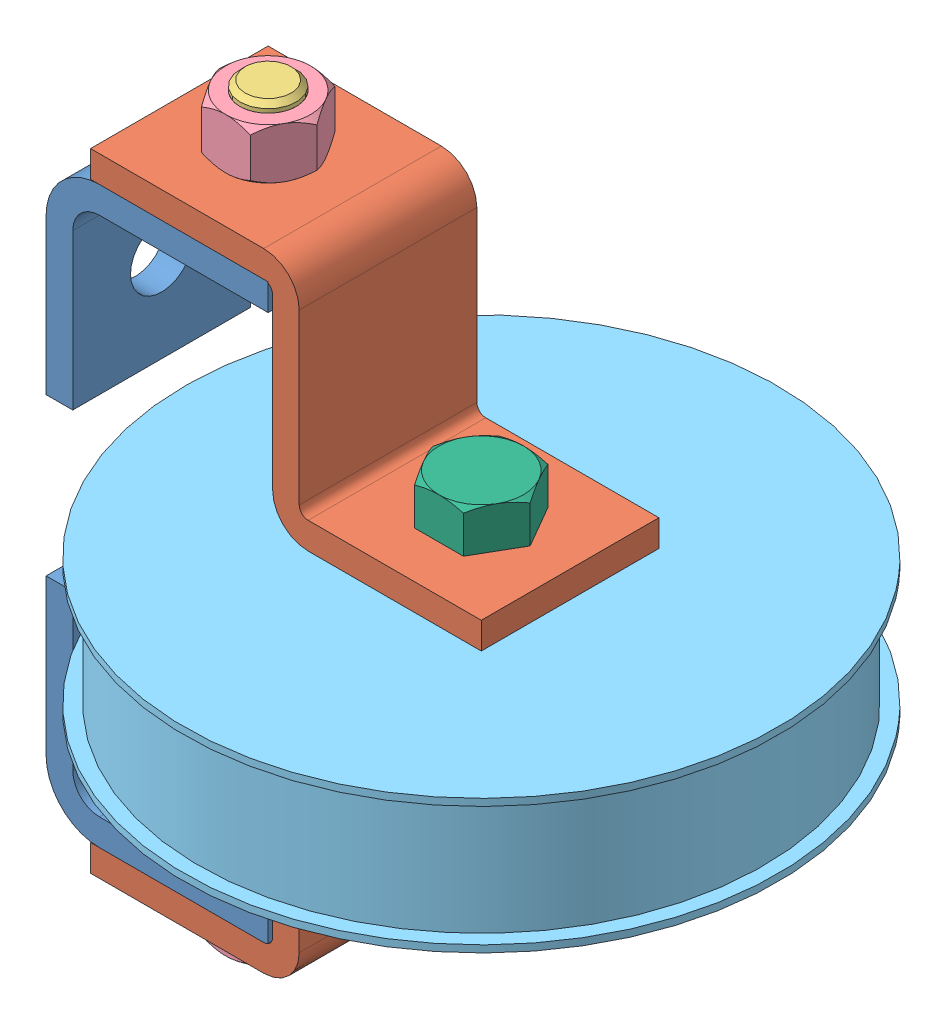
SolidWorks assembly Large Pulley Mount, configuration Default. Lengths in mm.
Overall size (187.97 168.14 187.97).
11 component instances, 5 part files, 17 mates.
Components (placement in the parent):
- P1026 - Unistrut 2-Hole 90 deg Fitting-1: P1026 - Unistrut 2-Hole 90 deg Fitting [Default] at (18.6827 -44.2712 5.2371) size (50 47 40)
- P1347 - Unistrut 2-Hole Z Fitting-1: P1347 - Unistrut 2-Hole Z Fitting [Default] at (28.6827 8.7288 -34.7629) x (1 0 0) z (0 0 -1) size (88 54 40)
- hex bolt_ai-3: hex bolt_ai [HBOLT 0.5000-13x1x1-N] at (48.6827 -12.5168 -14.7629) x (0 1 0) z (0 0 1) size (34.65 22 19.05)
- hex nut_ai-2: hex nut_ai [HNUT 0.5000-20-D-N] at (48.6827 20.108 -14.7629) x (0.866025 0 -0.5) z (0 1 0) size (19.05 22 11.38)
- Wide Pulley-2: Wide Pulley [5"x0.5"] at (96.6827 -61.9399 -14.7629) x (0.762017 0 -0.647557) z (0 -1 0) size (133.35 133.35 30.16)
- hex bolt_ai-2: hex bolt_ai [HBOLT 0.5000-20x3x3-N] at (96.6827 -30.0256 -14.7629) x (0 -1 0) z (0 0 1) size (85.45 22 19.05)
- P1026 - Unistrut 2-Hole 90 deg Fitting-2: P1026 - Unistrut 2-Hole 90 deg Fitting [Default] at (18.6827 -79.6087 -34.7629) x (1 0 0) z (0 0 -1) size (50 47 40)
- P1347 - Unistrut 2-Hole Z Fitting-2: P1347 - Unistrut 2-Hole Z Fitting [Default] at (28.6827 -132.6087 5.2371) size (88 54 40)
- hex bolt_ai-4: hex bolt_ai [HBOLT 0.5000-13x1x1-N] at (48.6827 -111.3631 -14.7629) x (0 -1 0) z (0 0 -1) size (34.65 22 19.05)
- hex nut_ai-3: hex nut_ai [HNUT 0.5000-20-D-N] at (48.6827 -132.6087 -14.7629) x (0.866025 0 -0.5) z (0 1 0) size (19.05 22 11.38)
- hex nut_ai-4: hex nut_ai [HNUT 0.5000-20-D-N] at (96.6827 -95.9879 -14.7629) x (0.866025 0 0.5) z (0 -1 0) size (19.05 22 11.38)
Mates (geometry in assembly coordinates):
- Concentric11: concentric aligned: cylinder of P1026 - Unistrut 2-Hole 90 deg Fitting-1 through (48.6827 -3.2712 -14.7629) axis (0 -1 0) radius 7; cylinder of hex bolt_ai-3 through (48.6827 -12.5168 -14.7629) axis (0 -1 0) radius 6.35
- Coincident21: coincident anti-aligned: plane of P1026 - Unistrut 2-Hole 90 deg Fitting-1 through (24.6827 -3.2712 5.2371) normal (0 -1 0); plane of hex bolt_ai-3 through (37.6841 -3.2712 -14.7629) normal (0 1 0)
- Concentric2: concentric anti-aligned: cylinder of P1347 - Unistrut 2-Hole Z Fitting-1 through (48.6827 8.7288 -14.7629) axis (0 1 0) radius 7; cylinder of hex bolt_ai-3 through (48.6827 -12.5168 -14.7629) axis (0 -1 0) radius 6.35
- Coincident5: coincident anti-aligned: plane of P1026 - Unistrut 2-Hole 90 deg Fitting-1 through (68.6827 2.7288 -34.7629) normal (0 1 0); plane of P1347 - Unistrut 2-Hole Z Fitting-1 through (28.6827 2.7288 5.2371) normal (0 -1 0)
- Parallel2: parallel aligned: plane of P1026 - Unistrut 2-Hole 90 deg Fitting-1 through (18.6827 2.7288 -34.7629) normal (-1 0 0); plane of P1347 - Unistrut 2-Hole Z Fitting-1 through (28.6827 8.7288 -34.7629) normal (-1 0 0)
- Concentric41: concentric anti-aligned: cylinder of hex bolt_ai-3 through (48.6827 -12.5168 -14.7629) axis (0 -1 0) radius 6.35; cylinder of hex nut_ai-2 through (48.6827 -4.9295 -14.7629) axis (0 1 0) radius 6.35
- Coincident81: coincident anti-aligned: plane of P1347 - Unistrut 2-Hole Z Fitting-1 through (116.6827 8.7288 -34.7629) normal (0 1 0); plane of hex nut_ai-2 through (43.1834 8.7288 -24.2879) normal (0 -1 0)
- Parallel3: parallel aligned: plane of hex bolt_ai-3 through (43.1834 -3.2712 -24.2879) normal (0 0 -1); plane of hex nut_ai-2 through (54.1819 8.7288 -24.2879) normal (0 0 -1)
- Parallel4: parallel aligned: plane of P1026 - Unistrut 2-Hole 90 deg Fitting-1 through (18.6827 -44.2712 -34.7629) normal (0 0 -1); plane of hex bolt_ai-3 through (43.1834 -3.2712 -24.2879) normal (0 0 -1)
- Concentric51: concentric anti-aligned: cylinder of P1347 - Unistrut 2-Hole Z Fitting-1 through (96.6827 -45.2712 -14.7629) axis (0 -1 0) radius 7; cylinder of hex bolt_ai-2 through (96.6827 -30.0256 -14.7629) axis (0 1 0) radius 6.35
- Coincident111: coincident anti-aligned: plane of P1347 - Unistrut 2-Hole Z Fitting-1 through (116.6827 -39.2712 5.2371) normal (0 1 0); plane of hex bolt_ai-2 through (107.6812 -39.2712 -14.7629) normal (0 -1 0)
- Concentric6: concentric anti-aligned: cylinder of Wide Pulley-2 through (96.6827 -46.8587 -14.7629) axis (0 -1 0) radius 6.35; cylinder of hex bolt_ai-2 through (96.6827 -30.0256 -14.7629) axis (0 1 0) radius 6.35
- Distance1: distance = 1.5875 mm anti-aligned: plane of Wide Pulley-2 through (96.6827 -46.8587 -14.7629) normal (0 1 0); plane of P1347 - Unistrut 2-Hole Z Fitting-1 through (28.6827 -45.2712 -34.7629) normal (0 -1 0)
- Concentric71: concentric anti-aligned: cylinder of hex bolt_ai-2 through (96.6827 -30.0256 -14.7629) axis (0 1 0) radius 6.35; cylinder of hex nut_ai-4 through (96.6827 -70.9504 -14.7629) axis (0 -1 0) radius 6.35
- Coincident131: coincident anti-aligned: plane of P1347 - Unistrut 2-Hole Z Fitting-2 through (116.6827 -84.6087 -34.7629) normal (0 -1 0); plane of hex nut_ai-4 through (91.1834 -84.6087 -5.2379) normal (0 1 0)
- Parallel5: parallel aligned: plane of hex bolt_ai-2 through (102.1819 -39.2712 -24.2879) normal (0 0 -1); plane of hex nut_ai-4 through (91.1834 -84.6087 -24.2879) normal (0 0 -1)
- Parallel6: parallel aligned: plane of P1347 - Unistrut 2-Hole Z Fitting-1 through (28.6827 8.7288 -34.7629) normal (0 0 -1); plane of hex bolt_ai-2 through (102.1819 -39.2712 -24.2879) normal (0 0 -1)
